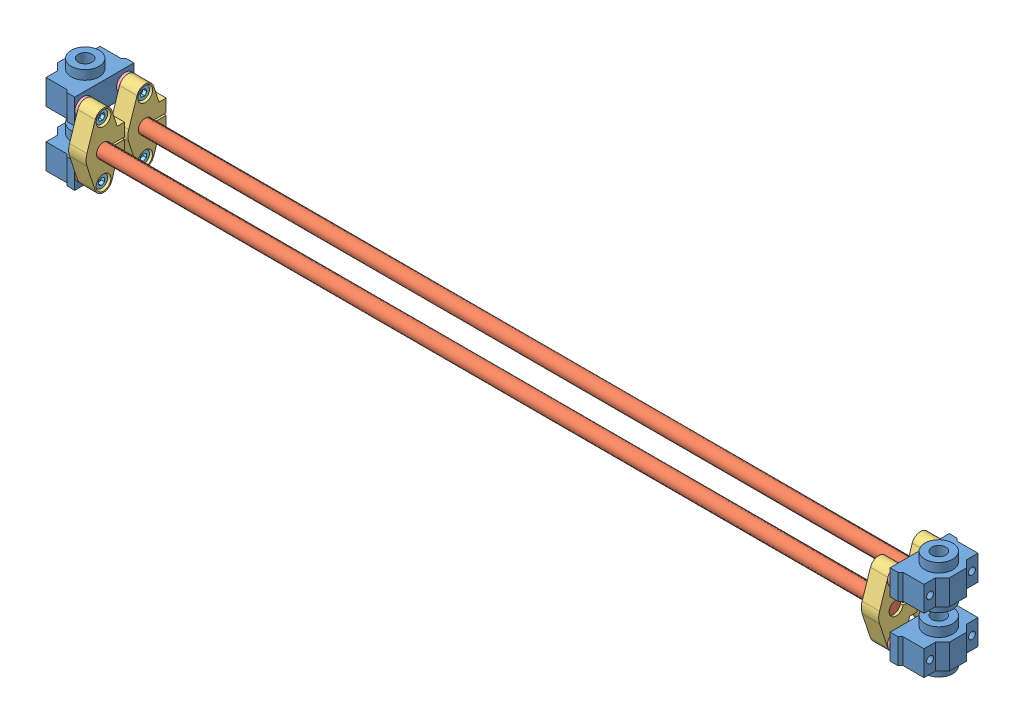
SolidWorks assembly 031Y轴活动机构-光轴-1, configuration Default. Lengths in mm.
Overall size (512 57 46).
26 component instances, 5 part files, 16 mates.
Components (placement in the parent):
- SCS箱式直线两孔光轴短滑块SCS8-1: SCS箱式直线两孔光轴短滑块SCS8 [默认] at (146.1198 269.0685 391.3915) x (0 0 1) z (-1 0 0) size (34 25 22)
- SCS箱式直线两孔光轴短滑块SCS8-2: SCS箱式直线两孔光轴短滑块SCS8 [默认] at (146.1198 237.0685 391.3915) x (0 0 1) z (-1 0 0) size (34 25 22)
- 光轴8mm465mmXY轴-1: 光轴8mm465mmXY轴 [默认] at (174.5315 253.0685 334.9209) x (0 -0.968895 -0.247471) z (1 0 0) size (8 8 465)
- 光轴8mm465mmXY轴-2: 光轴8mm465mmXY轴 [默认] at (176.1708 253.0685 310.9209) x (0 0.643777 -0.765213) z (1 0 0) size (8 8 465)
- SHF8光轴菱型卧式固定支撑座-9: SHF8光轴菱型卧式固定支撑座 [默认] at (176.0315 253.0685 310.9209) x (0 1 0) z (1 0 0) size (42 22 10)
- TW10尼龙凹凸垫圈4_10_7修剪-1: TW10尼龙凹凸垫圈4_10_7修剪 [默认] at (174.5315 237.0685 310.9209) x (0 0.47342 0.880837) z (0 0.880837 -0.47342) size (10 4.5 10)
- TW10尼龙凹凸垫圈4_10_7修剪-7: TW10尼龙凹凸垫圈4_10_7修剪 [默认] at (174.5315 269.0685 310.9209) x (0 -0.653979 -0.756513) z (0 -0.756513 0.653979) size (10 4.5 10)
- M4_10-1: M4_10 [默认] at (171.0315 237.0685 310.9209) x (0 0.014759 -0.999891) z (0 -0.999891 -0.014759) size (7 13.91 7)
- M4_10-7: M4_10 [默认] at (171.0315 269.0685 310.9209) x (0 -0.998446 0.055729) z (0 0.055729 0.998446) size (7 13.91 7)
- SHF8光轴菱型卧式固定支撑座-10: SHF8光轴菱型卧式固定支撑座 [默认] at (176.0315 253.0685 334.9209) x (0 1 0) z (1 0 0) size (42 22 10)
- SHF8光轴菱型卧式固定支撑座-11: SHF8光轴菱型卧式固定支撑座 [默认] at (631.0315 253.0685 334.9209) x (0 1 0) z (1 0 0) size (42 22 10)
- SHF8光轴菱型卧式固定支撑座-12: SHF8光轴菱型卧式固定支撑座 [默认] at (631.0315 253.0685 310.9209) x (0 1 0) z (1 0 0) size (42 22 10)
- TW10尼龙凹凸垫圈4_10_7修剪-9: TW10尼龙凹凸垫圈4_10_7修剪 [默认] at (642.5315 237.0685 310.9209) x (0 0.47342 0.880837) z (0 -0.880837 0.47342) size (10 4.5 10)
- M4_10-9: M4_10 [默认] at (646.0315 237.0685 310.9209) x (0 0.014759 -0.999891) z (0 0.999891 0.014759) size (7 13.91 7)
- TW10尼龙凹凸垫圈4_10_7修剪-10: TW10尼龙凹凸垫圈4_10_7修剪 [默认] at (642.5315 269.0685 310.9209) x (0 -0.653979 -0.756513) z (0 0.756513 -0.653979) size (10 4.5 10)
- M4_10-10: M4_10 [默认] at (646.0315 269.0685 310.9209) x (0 -0.998446 0.055729) z (0 -0.055729 -0.998446) size (7 13.91 7)
- M4_10-8: M4_10 [默认] at (171.0315 269.0685 334.9209) x (0 -0.998446 0.055729) z (0 0.055729 0.998446) size (7 13.91 7)
- TW10尼龙凹凸垫圈4_10_7修剪-8: TW10尼龙凹凸垫圈4_10_7修剪 [默认] at (174.5315 269.0685 334.9209) x (0 -0.653979 -0.756513) z (0 -0.756513 0.653979) size (10 4.5 10)
- M4_10-6: M4_10 [默认] at (171.0315 237.0685 334.9209) x (0 0.014759 -0.999891) z (0 -0.999891 -0.014759) size (7 13.91 7)
- TW10尼龙凹凸垫圈4_10_7修剪-6: TW10尼龙凹凸垫圈4_10_7修剪 [默认] at (174.5315 237.0685 334.9209) x (0 0.47342 0.880837) z (0 0.880837 -0.47342) size (10 4.5 10)
- TW10尼龙凹凸垫圈4_10_7修剪-11: TW10尼龙凹凸垫圈4_10_7修剪 [默认] at (642.5315 237.0685 334.9209) x (0 0.47342 0.880837) z (0 -0.880837 0.47342) size (10 4.5 10)
- M4_10-11: M4_10 [默认] at (646.0315 237.0685 334.9209) x (0 0.014759 -0.999891) z (0 0.999891 0.014759) size (7 13.91 7)
- TW10尼龙凹凸垫圈4_10_7修剪-12: TW10尼龙凹凸垫圈4_10_7修剪 [默认] at (642.5315 269.0685 334.9209) x (0 -0.653979 -0.756513) z (0 0.756513 -0.653979) size (10 4.5 10)
- M4_10-12: M4_10 [默认] at (646.0315 269.0685 334.9209) x (0 -0.998446 0.055729) z (0 -0.055729 -0.998446) size (7 13.91 7)
- SCS箱式直线两孔光轴短滑块SCS8-7: SCS箱式直线两孔光轴短滑块SCS8 [默认] at (670.9433 237.0685 254.4504) x (0 0 -1) z (1 0 0) size (34 25 22)
- SCS箱式直线两孔光轴短滑块SCS8-8: SCS箱式直线两孔光轴短滑块SCS8 [默认] at (670.9433 269.0685 254.4504) x (0 0 -1) z (1 0 0) size (34 25 22)
Mates (geometry in assembly coordinates):
- 平行1: parallel: plane of assembly through (408.5315 0 0) normal (1 0 0); plane of assembly; plane of assembly; plane of SCS箱式直线两孔光轴短滑块SCS8-2 through (174.5315 244.2685 305.9209) normal (1 0 0)
- 同心7: concentric: cylinder of SCS箱式直线两孔光轴短滑块SCS8-1 through (152.5315 269.0685 310.9209) axis (-1 0 0) radius 2; cylinder of M4_10-7 through (181.0315 269.0685 310.9209) axis (-1 0 0) radius 2
- 同心8: concentric: cylinder of assembly; cylinder of assembly; cylinder of SCS箱式直线两孔光轴短滑块SCS8-2 through (152.5315 237.0685 310.9209) axis (-1 0 0) radius 2; cylinder of M4_10-1 through (181.0315 237.0685 310.9209) axis (-1 0 0) radius 2
- 同心12: concentric: cylinder of assembly; cylinder of assembly; cylinder of TW10尼龙凹凸垫圈4_10_7修剪-1 through (176.0315 237.0685 310.9209) axis (-1 0 0) radius 2; cylinder of M4_10-1 through (181.0315 237.0685 310.9209) axis (-1 0 0) radius 2
- 同心13: concentric: cylinder of assembly; cylinder of assembly; cylinder of TW10尼龙凹凸垫圈4_10_7修剪-7 through (176.0315 269.0685 310.9209) axis (-1 0 0) radius 2; cylinder of M4_10-7 through (181.0315 269.0685 310.9209) axis (-1 0 0) radius 2
- 重合1: coincident: plane of assembly; plane of assembly; plane of SHF8光轴菱型卧式固定支撑座-9 through (176.0315 253.0685 310.9209) normal (-1 0 0); plane of TW10尼龙凹凸垫圈4_10_7修剪-1 through (176.0315 237.0685 310.9209) normal (1 0 0)
- 重合2: coincident: plane of assembly; plane of assembly; plane of SHF8光轴菱型卧式固定支撑座-9 through (176.0315 253.0685 310.9209) normal (-1 0 0); plane of TW10尼龙凹凸垫圈4_10_7修剪-7 through (176.0315 269.0685 310.9209) normal (1 0 0)
- 重合3: coincident: plane of assembly; plane of assembly; plane of SCS箱式直线两孔光轴短滑块SCS8-2 through (174.5315 244.2685 305.9209) normal (1 0 0); plane of TW10尼龙凹凸垫圈4_10_7修剪-1 through (174.5315 237.0685 310.9209) normal (-1 0 0)
- 重合4: coincident: plane of SCS箱式直线两孔光轴短滑块SCS8-1 through (174.5315 276.2685 305.9209) normal (1 0 0); plane of TW10尼龙凹凸垫圈4_10_7修剪-7 through (174.5315 269.0685 310.9209) normal (-1 0 0)
- 同心14: concentric: cylinder of assembly; cylinder of assembly; cylinder of SCS箱式直线两孔光轴短滑块SCS8-2 through (152.5315 237.0685 310.9209) axis (-1 0 0) radius 2; cylinder of M4_10-1 through (181.0315 237.0685 310.9209) axis (-1 0 0) radius 2
- 同心15: concentric: cylinder of SCS箱式直线两孔光轴短滑块SCS8-1 through (152.5315 269.0685 310.9209) axis (-1 0 0) radius 2; cylinder of M4_10-7 through (181.0315 269.0685 310.9209) axis (-1 0 0) radius 2
- 重合5: coincident: plane of assembly; plane of assembly; plane of SHF8光轴菱型卧式固定支撑座-9 through (181.0315 253.0685 310.9209) normal (1 0 0); plane of M4_10-1 through (181.0315 237.0685 310.9209) normal (-1 0 0)
- 重合6: coincident: plane of assembly; plane of assembly; plane of SHF8光轴菱型卧式固定支撑座-9 through (181.0315 253.0685 310.9209) normal (1 0 0); plane of M4_10-7 through (181.0315 269.0685 310.9209) normal (-1 0 0)
- 同心18: concentric: cylinder of assembly; cylinder of assembly; cylinder of 光轴8mm465mmXY轴-2 through (641.1708 253.0685 310.9209) axis (-1 0 0) radius 4; cylinder of SHF8光轴菱型卧式固定支撑座-9 through (186.0315 253.0685 310.9209) axis (-1 0 0) radius 4
- 同心19: concentric: cylinder of assembly; cylinder of assembly; cylinder of SHF8光轴菱型卧式固定支撑座-9 through (181.0315 269.0685 310.9209) axis (-1 0 0) radius 2.75; cylinder of TW10尼龙凹凸垫圈4_10_7修剪-7 through (179.0315 269.0685 310.9209) axis (-1 0 0) radius 2.5
- 同心20: concentric: cylinder of assembly; cylinder of assembly; cylinder of SHF8光轴菱型卧式固定支撑座-9 through (181.0315 237.0685 310.9209) axis (-1 0 0) radius 2.75; cylinder of TW10尼龙凹凸垫圈4_10_7修剪-1 through (179.0315 237.0685 310.9209) axis (-1 0 0) radius 2.5
